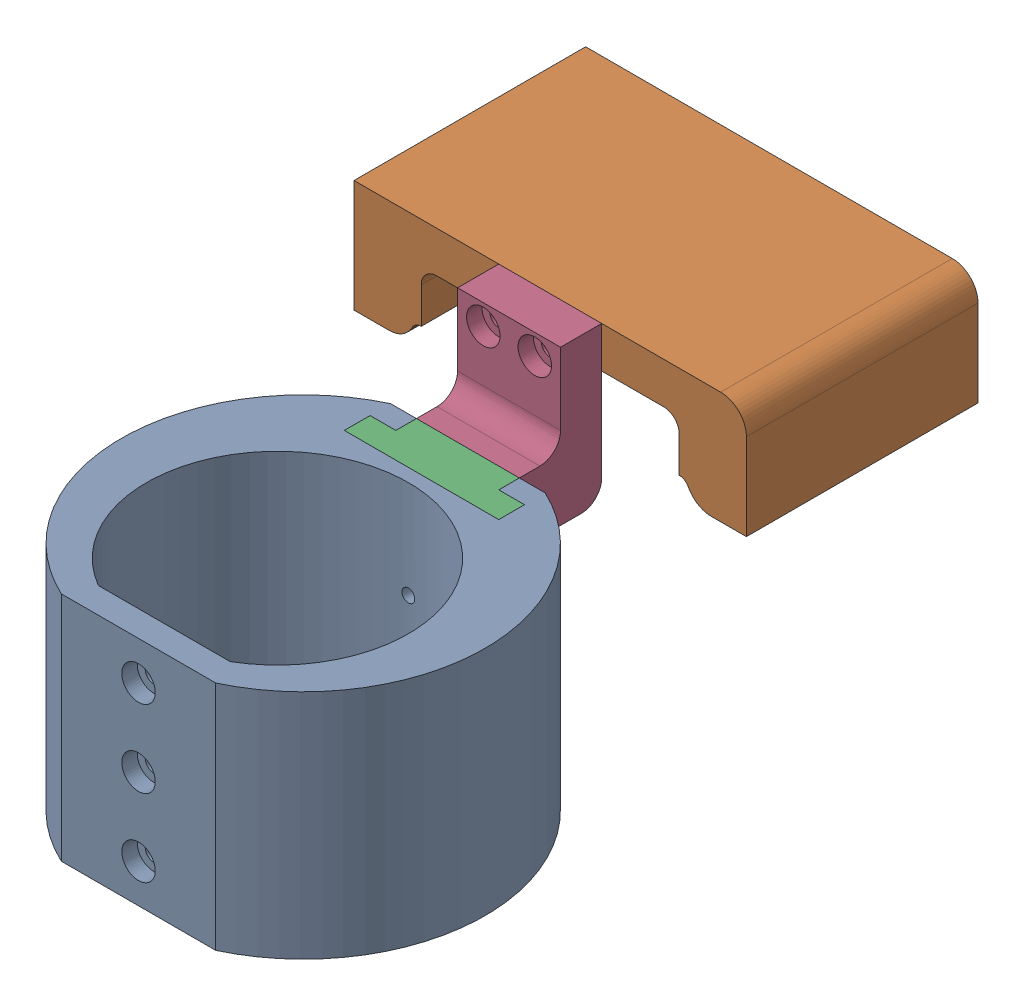
SolidWorks assembly zeiss_multipart - v4, configuration Default. Lengths in mm.
Overall size (76.24 63 124.99).
3 component instances, 3 part files, 6 mates.
Components (placement in the parent):
- zeiss_mount_bracket_1 -v4-1: zeiss_mount_bracket_1 -v4 [2in] at origin size (70.68 45 63.99)
- zeiss_mount_bracket_2 - v4-1: zeiss_mount_bracket_2 - v4 [Modified bracket] at (0 22.49 -97.997) x (-1 0 0) z (0 -1 0) size (76.24 45 21.82)
- zeiss_mount_bracket_3 - v4-1: zeiss_mount_bracket_3 - v4 [Default] at (0 16.5 -36.997) x (0 0 -1) z (1 0 0) size (25 54 30)
Mates (geometry in assembly coordinates):
- Coincident1: coincident anti-aligned: plane of zeiss_mount_bracket_1 -v4-1 through (0 -13.5 0) normal (0 1 0); plane of zeiss_mount_bracket_3 - v4-1 through (0 -13.5 -36.997) normal (0 -1 0)
- Width1: width anti-aligned: plane of zeiss_mount_bracket_3 - v4-1 through (15 -13.5 -27.997) normal (1 0 0); plane of zeiss_mount_bracket_1 -v4-1 through (-15 -13.5 -32.997) normal (-1 0 0); plane of zeiss_mount_bracket_3 - v4-1 through (15 -13.5 -27.997) normal (-1 0 0); plane of zeiss_mount_bracket_1 -v4-1 through (-15 -13.5 -32.997) normal (1 0 0)
- Width2: width anti-aligned: plane of zeiss_mount_bracket_1 -v4-1 through (-15 -13.5 -27.997) normal (0 0 -1); plane of zeiss_mount_bracket_3 - v4-1 through (15 -13.5 -32.997) normal (0 0 1); plane of zeiss_mount_bracket_1 -v4-1 through (-15 -13.5 -27.997) normal (0 0 1); plane of zeiss_mount_bracket_3 - v4-1 through (15 -13.5 -32.997) normal (0 0 -1)
- Coincident2: coincident anti-aligned: plane of zeiss_mount_bracket_2 - v4-1 through (0 22.49 -52.997) normal (0 0 1); plane of zeiss_mount_bracket_3 - v4-1 through (10 30.5 -52.997) normal (0 0 -1)
- Width3: width: plane of zeiss_mount_bracket_2 - v4-1 through (-38.12 22.49 -87.997) normal (-1 0 0); plane of zeiss_mount_bracket_3 - v4-1 through (38.12 22.49 -87.997) normal (1 0 0); plane of zeiss_mount_bracket_2 - v4-1 through (15 30.5 -13.4524) normal (1 0 0); plane of zeiss_mount_bracket_3 - v4-1 through (-15 30.5 -13.4524) normal (-1 0 0)
- Coincident4: coincident aligned: plane of zeiss_mount_bracket_2 - v4-1 through (38.12 40.5 -11.104) normal (0 1 0); plane of zeiss_mount_bracket_3 - v4-1 through (10 40.5 -22.6364) normal (0 1 0)
